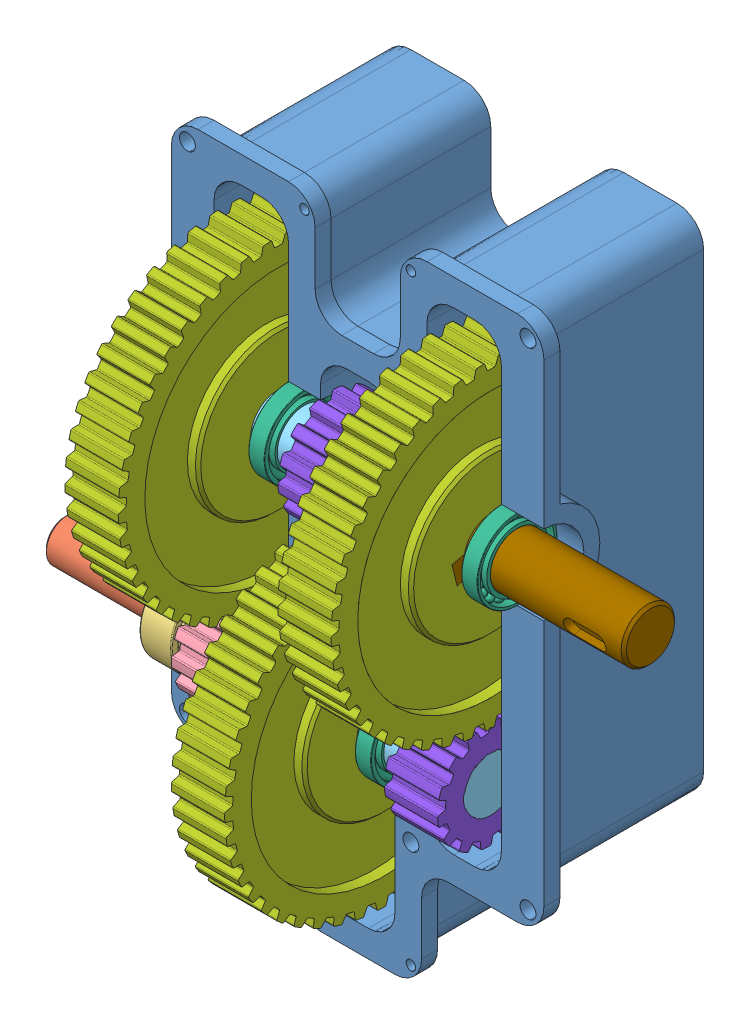
SolidWorks assembly Gear Reducer 2003091, configuration Default. Lengths in mm.
Overall size (110 120.14 82.28).
15 component instances, 9 part files, 32 mates.
Components (placement in the parent):
- 7 Housing 2003091-1: 7 Housing 2003091 [Default] at (-49.8572 2.2273 7.2958) size (70 119 35)
- 1. Input Shaft 2003091-1: 1. Input Shaft 2003091 [Default] at (-104.8572 -17.2727 42.2958) x (0 -0.409881 -0.912139) z (1 0 0) size (8.74 9 40)
- radial ball bearing_68_iso-1: radial ball bearing_68_iso [ISO 15 RBB - 388 - 12,DE,NC,12_68] at (-79.8572 -17.2727 42.2958) x (-1 0 0) z (0 0 -1) size (6 16 16)
- 4 Input Gear 2003091-1: 4 Input Gear 2003091 [Default] at (-64.8572 -17.2727 42.2958) x (0 0.409881 0.912139) z (-1 0 0) size (20 19.79 10)
- 2 Speed shaft 2003091-1: 2 Speed shaft 2003091 [Default] at (-44.8572 21.7273 42.2958) x (0 -0.345959 -0.93825) z (-1 0 0) size (10.23 12.11 30)
- angular contact ball bearing_68_iso-1: angular contact ball bearing_68_iso [ISO 15 ABB - 1710 - 20,SI,NC,20_68] at (-61.3572 21.7273 42.2958) size (3 15 15)
- 5 Output Gear 2003091-1: 5 Output Gear 2003091 [Default] at (-74.8572 21.7273 42.2958) x (0 0.345959 0.93825) z (1 0 0) size (59.99 59.96 10)
- 6 Middle Gear 2003091-1: 6 Middle Gear 2003091 [Default] at (-54.8572 21.7273 42.2958) x (0 0.345959 0.93825) z (1 0 0) size (20 19.79 10)
- 2 Speed shaft 2003091-2: 2 Speed shaft 2003091 [Default] at (-24.8572 -17.2727 42.2958) x (0 0.857637 -0.514256) z (-1 0 0) size (10.23 12.11 30)
- angular contact ball bearing_68_iso-2: angular contact ball bearing_68_iso [ISO 15 ABB - 1710 - 20,SI,NC,20_68] at (-41.3572 -17.2727 42.2958) size (3 15 15)
- 5 Output Gear 2003091-2: 5 Output Gear 2003091 [Default] at (-54.8572 -17.2727 42.2958) x (0 -0.857637 0.514256) z (1 0 0) size (59.99 59.96 10)
- 6 Middle Gear 2003091-2: 6 Middle Gear 2003091 [Default] at (-34.8572 -17.2727 42.2958) x (0 -0.857637 0.514256) z (1 0 0) size (20 19.79 10)
- 3 Output Shaft 2003091-1: 3 Output Shaft 2003091 [Default] at (-34.8572 21.7273 42.2958) x (0 0.9712 0.238267) z (1 0 0) size (10 12 40)
- angular contact ball bearing_68_iso-3: angular contact ball bearing_68_iso [ISO 15 ABB - 1710 - 20,DE,NC,20_68] at (-21.3572 21.7273 42.2958) x (-1 0 0) z (0 -0.598697 -0.800975) size (3 15 15)
- 5 Output Gear 2003091-3: 5 Output Gear 2003091 [Default] at (-24.8572 21.7273 42.2958) x (0 -0.9712 -0.238267) z (-1 0 0) size (59.99 59.96 10)
Mates (geometry in assembly coordinates):
- Concentric1: concentric aligned: cylinder of 7 Housing 2003091-1 through (-76.8572 -17.2727 42.2958) axis (-1 0 0) radius 8; cylinder of 1. Input Shaft 2003091-1 through (-64.8572 -17.2727 42.2958) axis (-1 0 0) radius 4
- Concentric2: concentric aligned: cylinder of 1. Input Shaft 2003091-1 through (-64.8572 -17.2727 42.2958) axis (-1 0 0) radius 4; cylinder of radial ball bearing_68_iso-1 through (-59.2197 -17.2727 42.2958) axis (-1 0 0) radius 4
- Coincident2: coincident aligned: plane of 7 Housing 2003091-1 through (-76.8572 56.7273 10.2958) normal (1 0 0); plane of radial ball bearing_68_iso-1 through (-76.8572 -10.4727 42.2958) normal (1 0 0)
- Coincident3: coincident anti-aligned: plane of 7 Housing 2003091-1 through (-49.8572 2.2273 42.2958) normal (0 0 1); plane of radial ball bearing_68_iso-1 through (-79.8572 -17.2727 42.2958) normal (0 0 -1)
- Concentric3: concentric anti-aligned: cylinder of 1. Input Shaft 2003091-1 through (-64.8572 -17.2727 42.2958) axis (-1 0 0) radius 4; cylinder of 4 Input Gear 2003091-1 through (-74.8572 -17.2727 42.2958) axis (1 0 0) radius 4
- Coincident4: coincident anti-aligned: line of 1. Input Shaft 2003091-1 through (-64.8572 -12.8065 42.9226) axis (0 -0.204541 0.978858); line of 4 Input Gear 2003091-1 through (-64.8572 -12.9292 43.5099) axis (0 0.204541 -0.978858)
- Distance1: distance = 2 mm anti-aligned: plane of 7 Housing 2003091-1 through (-76.8572 56.7273 10.2958) normal (1 0 0); plane of 4 Input Gear 2003091-1 through (-74.8572 -17.2727 42.2958) normal (-1 0 0)
- Concentric4: concentric anti-aligned: cylinder of 7 Housing 2003091-1 through (-56.8572 21.7273 42.2958) axis (-1 0 0) radius 7.5; cylinder of 2 Speed shaft 2003091-1 through (-74.8572 21.7273 42.2958) axis (1 0 0) radius 5.1145
- Concentric5: concentric aligned: cylinder of 2 Speed shaft 2003091-1 through (-74.8572 21.7273 42.2958) axis (1 0 0) radius 5.1145; cylinder of angular contact ball bearing_68_iso-1 through (-81.9947 21.7273 42.2958) axis (1 0 0) radius 5
- Coincident6: coincident aligned: plane of 7 Housing 2003091-1 through (-62.8572 56.7273 10.2958) normal (-1 0 0); plane of angular contact ball bearing_68_iso-1 through (-62.8572 28.7023 42.2958) normal (-1 0 0)
- Concentric6: concentric anti-aligned: cylinder of 2 Speed shaft 2003091-1 through (-74.8572 21.7273 42.2958) axis (1 0 0) radius 5.1145; cylinder of 5 Output Gear 2003091-1 through (-64.8572 21.7273 42.2958) axis (-1 0 0) radius 5
- Coincident7: coincident aligned: line of 2 Speed shaft 2003091-1 through (-74.8572 14.4676 42.841) axis (0 0.345959 0.93825); line of 5 Output Gear 2003091-1 through (-74.8572 14.4676 42.841) axis (0 0.345959 0.93825)
- Coincident8: coincident aligned: plane of 4 Input Gear 2003091-1 through (-74.8572 -17.2727 42.2958) normal (-1 0 0); plane of 5 Output Gear 2003091-1 through (-74.8572 21.7273 42.2958) normal (-1 0 0)
- GearMate1: gear = 60 : 20 mm: cylinder of 4 Input Gear 2003091-1 through (-74.8572 -17.2727 42.2958) axis (1 0 0) radius 10; cylinder of 5 Output Gear 2003091-1 through (-64.8572 21.7273 42.2958) axis (-1 0 0) radius 30
- Concentric7: concentric anti-aligned: cylinder of 2 Speed shaft 2003091-1 through (-74.8572 21.7273 42.2958) axis (1 0 0) radius 5.1145; cylinder of 6 Middle Gear 2003091-1 through (-44.8572 21.7273 42.2958) axis (-1 0 0) radius 5
- Coincident10: coincident anti-aligned: line of 2 Speed shaft 2003091-1 through (-44.8572 14.4676 42.841) axis (0 0.345959 0.93825); line of 6 Middle Gear 2003091-1 through (-44.8572 15.8515 46.594) axis (0 -0.345959 -0.93825)
- Concentric8: concentric anti-aligned: cylinder of 7 Housing 2003091-1 through (-36.8572 -17.2727 42.2958) axis (-1 0 0) radius 7.5; cylinder of 2 Speed shaft 2003091-2 through (-54.8572 -17.2727 42.2958) axis (1 0 0) radius 5.1145
- Concentric9: concentric aligned: cylinder of 2 Speed shaft 2003091-2 through (-54.8572 -17.2727 42.2958) axis (1 0 0) radius 5.1145; cylinder of angular contact ball bearing_68_iso-2 through (-61.9947 -17.2727 42.2958) axis (1 0 0) radius 5
- Coincident12: coincident aligned: plane of 7 Housing 2003091-1 through (-42.8572 36.7273 10.2958) normal (-1 0 0); plane of angular contact ball bearing_68_iso-2 through (-42.8572 -10.2977 42.2958) normal (-1 0 0)
- Concentric10: concentric anti-aligned: cylinder of 2 Speed shaft 2003091-2 through (-54.8572 -17.2727 42.2958) axis (1 0 0) radius 5.1145; cylinder of 5 Output Gear 2003091-2 through (-44.8572 -17.2727 42.2958) axis (-1 0 0) radius 5
- Coincident13: coincident aligned: line of 2 Speed shaft 2003091-2 through (-54.8572 -19.1572 35.2638) axis (0 -0.857637 0.514256); line of 5 Output Gear 2003091-2 through (-54.8572 -19.1572 35.2638) axis (0 -0.857637 0.514256)
- Coincident14: coincident aligned: plane of 6 Middle Gear 2003091-1 through (-44.8572 21.7273 42.2958) normal (1 0 0); plane of 5 Output Gear 2003091-2 through (-44.8572 -17.2727 42.2958) normal (1 0 0)
- GearMate2: gear = 60 : 20 mm: cylinder of 6 Middle Gear 2003091-1 through (-44.8572 21.7273 42.2958) axis (-1 0 0) radius 10; cylinder of 5 Output Gear 2003091-2 through (-44.8572 -17.2727 42.2958) axis (-1 0 0) radius 30
- Concentric11: concentric anti-aligned: cylinder of 2 Speed shaft 2003091-2 through (-54.8572 -17.2727 42.2958) axis (1 0 0) radius 5.1145; cylinder of 6 Middle Gear 2003091-2 through (-24.8572 -17.2727 42.2958) axis (-1 0 0) radius 5
- Coincident15: coincident anti-aligned: line of 2 Speed shaft 2003091-2 through (-24.8572 -19.1572 35.2638) axis (0 -0.857637 0.514256); line of 6 Middle Gear 2003091-2 through (-24.8572 -22.5878 37.3208) axis (0 0.857637 -0.514256)
- Concentric12: concentric anti-aligned: cylinder of 7 Housing 2003091-1 through (-22.8572 21.7273 42.2958) axis (1 0 0) radius 7.5; cylinder of 3 Output Shaft 2003091-1 through (-24.8572 21.7273 42.2958) axis (-1 0 0) radius 5
- Concentric13: concentric aligned: cylinder of 3 Output Shaft 2003091-1 through (-24.8572 21.7273 42.2958) axis (-1 0 0) radius 5; cylinder of angular contact ball bearing_68_iso-3 through (-0.7197 21.7273 42.2958) axis (-1 0 0) radius 5
- Coincident16: coincident aligned: plane of 7 Housing 2003091-1 through (-22.8572 56.7273 10.2958) normal (-1 0 0); plane of angular contact ball bearing_68_iso-3 through (-22.8572 27.6545 37.8654) normal (-1 0 0)
- Concentric14: concentric anti-aligned: cylinder of 3 Output Shaft 2003091-1 through (-24.8572 21.7273 42.2958) axis (-1 0 0) radius 5; cylinder of 5 Output Gear 2003091-3 through (-34.8572 21.7273 42.2958) axis (1 0 0) radius 5
- Coincident17: coincident aligned: line of 3 Output Shaft 2003091-1 through (-34.8572 22.0018 49.5707) axis (0 -0.9712 -0.238267); line of 5 Output Gear 2003091-3 through (-34.8572 22.0018 49.5707) axis (0 -0.9712 -0.238267)
- Coincident18: coincident aligned: plane of 6 Middle Gear 2003091-2 through (-24.8572 -17.2727 42.2958) normal (1 0 0); plane of 5 Output Gear 2003091-3 through (-24.8572 21.7273 42.2958) normal (1 0 0)
- GearMate4: gear = 60 : 20 mm: cylinder of 6 Middle Gear 2003091-2 through (-24.8572 -17.2727 42.2958) axis (-1 0 0) radius 10; cylinder of 5 Output Gear 2003091-3 through (-34.8572 21.7273 42.2958) axis (1 0 0) radius 30
